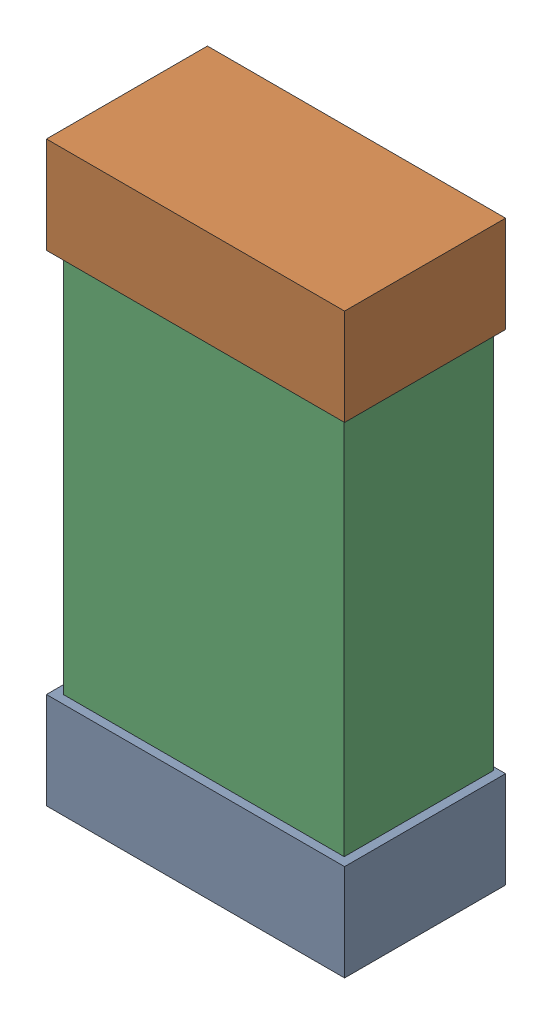
SolidWorks assembly R37, configuration Default. Lengths in mm.
Overall size (0.85 1.65 0.46).
6 component instances, 2 part files, 0 mates.
Components (placement in the parent):
- 432138512_30-1: 432138512_30 [Default] at (10.8249 49.4142 -0.8715) size (0.85 0.28 0.46)
  - Extruded-1: Extruded [Default] at origin size (0.85 0.28 0.46)
- 432138512_31-1: 432138512_31 [Default] at (10.8249 50.7857 -0.8715) size (0.85 0.28 0.46)
  - Extruded-1: Extruded [Default] at origin size (0.85 0.28 0.46)
- 432124816_15-1: 432124816_15 [Default] at (10.8249 50.0999 -0.8615) size (0.8 1.5 0.42)
  - Extruded (1)-1: Extruded (1) [Default] at origin size (0.8 1.5 0.42)
